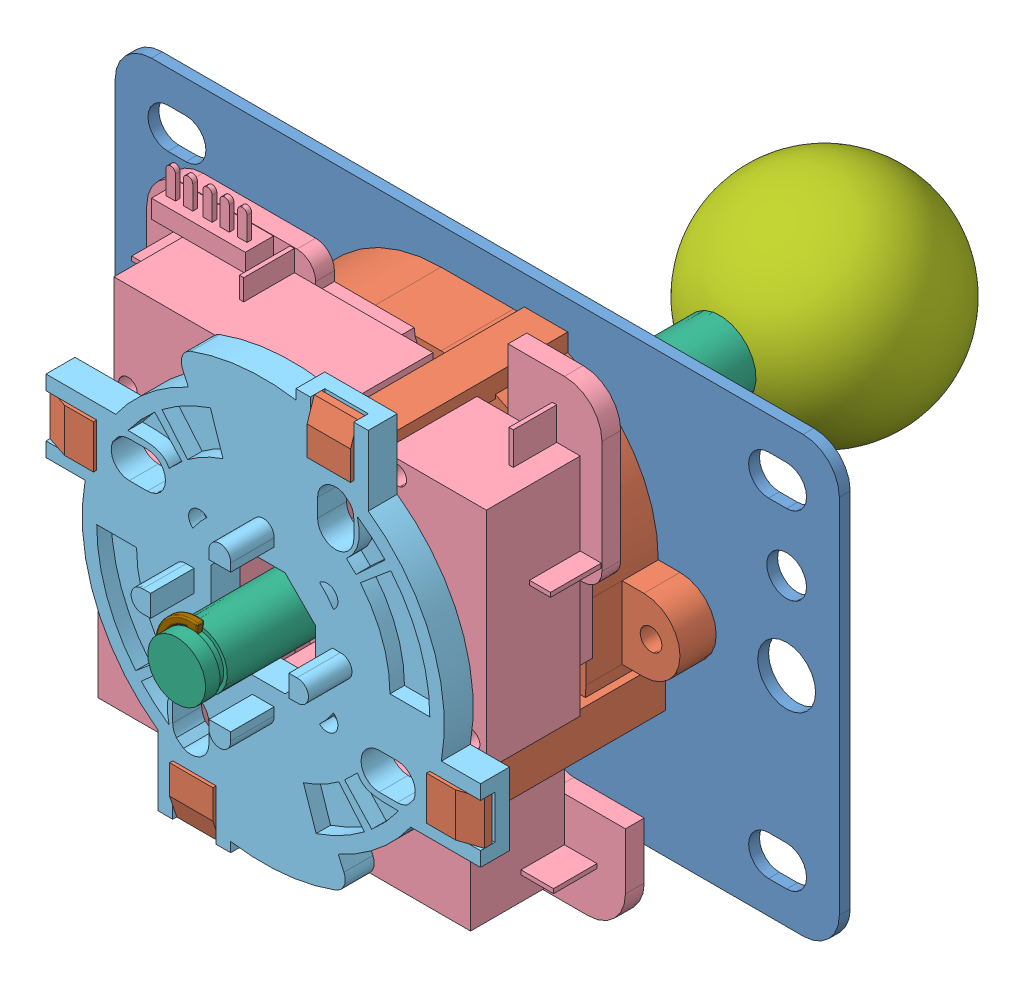
SolidWorks assembly Joystick Sanwa -Mod JLF-TP-8YT-W 1, configuration Predeterminado. Lengths in mm.
Overall size (100 66.68 104.46).
9 component instances, 9 part files, 7 mates.
Components (placement in the parent):
- SANWA_JOYSTICK_3-1: SANWA_JOYSTICK_3 [Predeterminado] at origin size (100 60 1.5)
- SSANWA_JOYSTICK_6-1: SSANWA_JOYSTICK_6 [Predeterminado] at origin size (66 60 30)
- SANWA_JOYSTICK_2-1: SANWA_JOYSTICK_2 [Predeterminado] x (1 0 0) z (0 1 0) size (39.99 20.68 39.98)
- SANWA_JOYSTICK_5-1: SANWA_JOYSTICK_5 [Predeterminado] at (0 0 12.592) x (1 0 0) z (0 0 -1) size (66.1 66.68 17.11)
- GT-Y-1: GT-Y [Predeterminado] at (0 0 27.552) size (60 60 10)
- SANWA_JOYSTICK_0-1: SANWA_JOYSTICK_0 [Predeterminado] at (0 0 7.5029) x (0.996812 -0.079782 0) z (0.079782 0.996812 0) size (10 85 10)
- BALL-1: BALL [Predeterminado] at (0 0 -47.9539) x (0.999996 -0.002826 0) z (0.002826 0.999996 0) size (30 30 30)
- DUSTER-1: DUSTER [Predeterminado] at (0 0 -6.2) x (-1 0 0) z (0 0 1) size (40 40 0.5)
- E-1: E [Predeterminado] at (0 0 39.0029) x (0.999996 -0.002826 0) z (0.002826 0.999996 0) size (5.88 1.1 10)
Mates (geometry in assembly coordinates):
- Concéntrica2: concentric aligned: cylinder of SANWA_JOYSTICK_2-1 through (0 0 -0.5) axis (0 0 1) radius 5; cylinder of SANWA_JOYSTICK_0-1 through (0 0 7.5029) axis (0 0 1) radius 4
- Concéntrica3: concentric anti-aligned: cylinder of SANWA_JOYSTICK_0-1 through (0 0 7.5029) axis (0 0 1) radius 3.5; cylinder of E-1 through (0 0 39.5029) axis (0 0 -1) radius 3.5
- Coincidente1: coincident anti-aligned: plane of SANWA_JOYSTICK_0-1 through (0 0 39.5029) normal (0 0 -1); plane of E-1 through (0 0 39.5029) normal (0 0 1)
- Concéntrica4: concentric anti-aligned: cylinder of SANWA_JOYSTICK_0-1 through (0 0 7.5029) axis (0 0 1) radius 4; cylinder of BALL-1 through (0 0 -47.9539) axis (0 0 -1) radius 4
- Coincidente2: coincident aligned: plane of SANWA_JOYSTICK_0-1 through (0 0 -33.4971) normal (0 0 -1); circle of BALL-1
- Concéntrica5: concentric aligned: cylinder of SANWA_JOYSTICK_0-1 through (0 0 7.5029) axis (0 0 1) radius 5; cylinder of DUSTER-1 through (0 0 -6.2) axis (0 0 1) radius 5
- Distancia1: distance = 4.2 mm anti-aligned: plane of DUSTER-1 through (0 0 -5.7) normal (0 0 1); plane of SANWA_JOYSTICK_3-1 through (0 0 -1.5) normal (0 0 -1)
